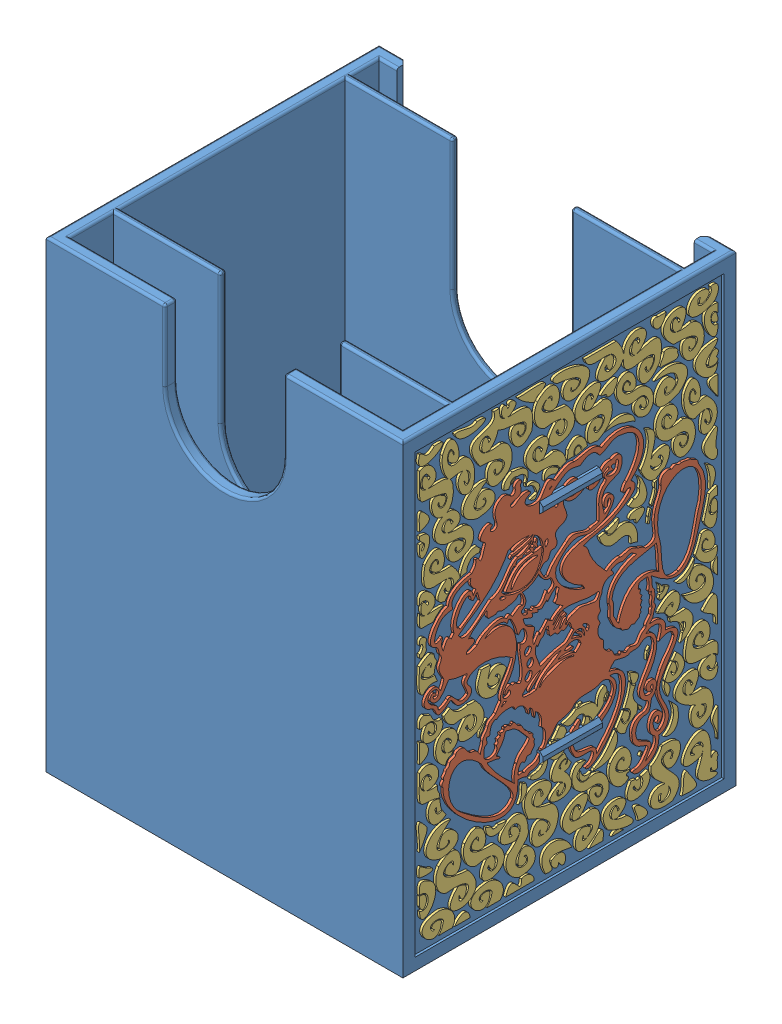
SolidWorks assembly Devil Box G5, configuration Default. Lengths in mm.
Overall size (77.66 99.06 71.12).
5 component instances, 3 part files, 8 mates.
Components (placement in the parent):
- Deck Box - B Type-2: Deck Box - B Type [Sides For Designs] at (61.6909 22.4247 -116.3955) size (77.66 99.06 71.12)
- Gear5Luffy-2-1: Gear5Luffy-2 [Default] at (35.3028 132.7186 -167.9459) x (0 0 1) z (-1 0 0) size (60.62 66.93 0.52)
- Gear5Luffy-2-2: Gear5Luffy-2 [Default] at (110.4868 132.9879 173.7989) x (0 0 -1) z (1 0 0) size (60.62 66.93 0.52)
- Box Design - Devil Fruit w G5 Luffy-1: Box Design - Devil Fruit w G5 Luffy [Default] at (110.4868 65.3069 1.432) x (0 0 -1) z (1 0 0) size (65.14 92.73 0.51)
- Box Design - Devil Fruit w G5 Luffy-2: Box Design - Devil Fruit w G5 Luffy [Default] at (35.3028 65.2439 4.4352) x (0 0 1) z (-1 0 0) size (65.14 92.73 0.51)
Mates (geometry in assembly coordinates):
- Coincident1: coincident anti-aligned: plane of Box Design - Devil Fruit-1 through (33.6158 45.0532 -30.5438) normal (0 -1 0); plane of Deck Box - B Type-1 through (48.0977 37.2892 -22.3855) normal (0 1 0)
- Coincident4: coincident: plane of Deck Box - B Type-1 through (50.6377 -11.5067 -22.3855) normal (1 0 0); plane of Deck Box - A Type-1 through (50.6377 -11.5067 -24.8989) normal (1 0 0)
- Coincident5: coincident: plane of Deck Box - B Type-1 through (-48.4223 -11.5067 132.4982) normal (0 0 1); plane of Deck Box - A Type-1 through (-48.4223 -11.5067 132.4982) normal (0 0 1)
- Coincident6: coincident aligned: plane of Deck Box - B Type-1 through (-48.4223 -38.4028 -22.3855) normal (0 -1 0); plane of Deck Box - A Type-1 through (-48.4223 -38.4028 -24.8989) normal (0 -1 0)
- Coincident8: coincident anti-aligned: plane of Deck Box - B Type-2 through (35.3028 22.4247 -116.3955) normal (-1 0 0); plane of Box Design - Devil Fruit w G5 Luffy-2 through (35.3028 65.2439 4.4352) normal (1 0 0)
- Coincident9: coincident anti-aligned: plane of Deck Box - B Type-2 through (35.3028 22.4247 -116.3955) normal (-1 0 0); plane of Gear5Luffy-2-1 through (35.3028 132.7186 -167.9459) normal (1 0 0)
- Coincident11: coincident anti-aligned: plane of Deck Box - B Type-2 through (110.4868 22.4247 -116.3955) normal (1 0 0); plane of Gear5Luffy-2-2 through (110.4868 132.9879 173.7989) normal (-1 0 0)
- Coincident12: coincident anti-aligned: plane of Deck Box - B Type-2 through (110.4868 22.4247 -116.3955) normal (1 0 0); plane of Box Design - Devil Fruit w G5 Luffy-1 through (110.4868 65.3069 1.432) normal (-1 0 0)
